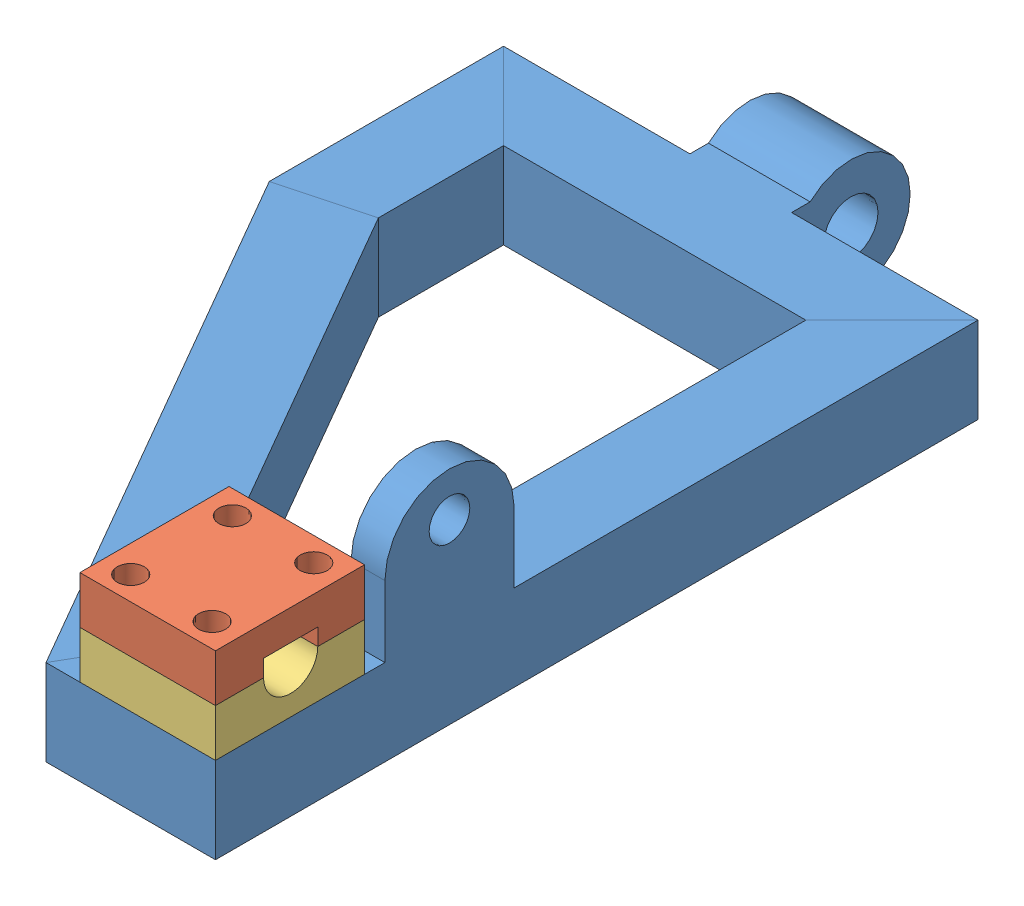
SolidWorks assembly wishbone_assemA, configuration Default. Lengths in mm.
Overall size (140 70.2 255.5).
3 component instances, 3 part files, 6 mates.
Components (placement in the parent):
- wishboneB-1: wishboneB [Default] at (107.6823 76.1104 267.1398) x (-1 0 0) z (0 0 1) size (140 70.2 255.5)
- motorFitting_1-1: motorFitting_1 [Default] at (91.2399 115.5104 244.9509) x (0 0 -1) z (1 0 0) size (44 14 40)
- motorFitting_2-1: motorFitting_2 [Default] at (91.2399 101.5104 244.9509) x (0 0 -1) z (1 0 0) size (44 14 40)
Mates (geometry in assembly coordinates):
- Coincident1: coincident aligned: plane of wishboneB-1 through (57.6823 76.1104 267.1398) normal (0 0 1); plane of motorFitting_2-1 through (67.6823 115.5104 267.1398) normal (0 0 1)
- Coincident2: coincident aligned: plane of wishboneB-1 through (107.6823 76.1104 267.1398) normal (1 0 0); plane of motorFitting_2-1 through (107.6823 115.5104 267.1398) normal (1 0 0)
- Coincident3: coincident anti-aligned: plane of wishboneB-1 through (57.6823 101.5104 267.1398) normal (0 1 0); plane of motorFitting_2-1 through (91.2399 101.5104 244.9509) normal (0 -1 0)
- Coincident4: coincident aligned: plane of motorFitting_1-1 through (67.6823 129.5104 267.1398) normal (0 0 1); plane of motorFitting_2-1 through (67.6823 115.5104 267.1398) normal (0 0 1)
- Coincident5: coincident aligned: plane of motorFitting_1-1 through (107.6823 129.5104 267.1398) normal (1 0 0); plane of motorFitting_2-1 through (107.6823 115.5104 267.1398) normal (1 0 0)
- Coincident6: coincident anti-aligned: plane of motorFitting_1-1 through (91.2399 115.5104 244.9509) normal (0 -1 0); plane of motorFitting_2-1 through (91.2399 115.5104 244.9509) normal (0 1 0)
